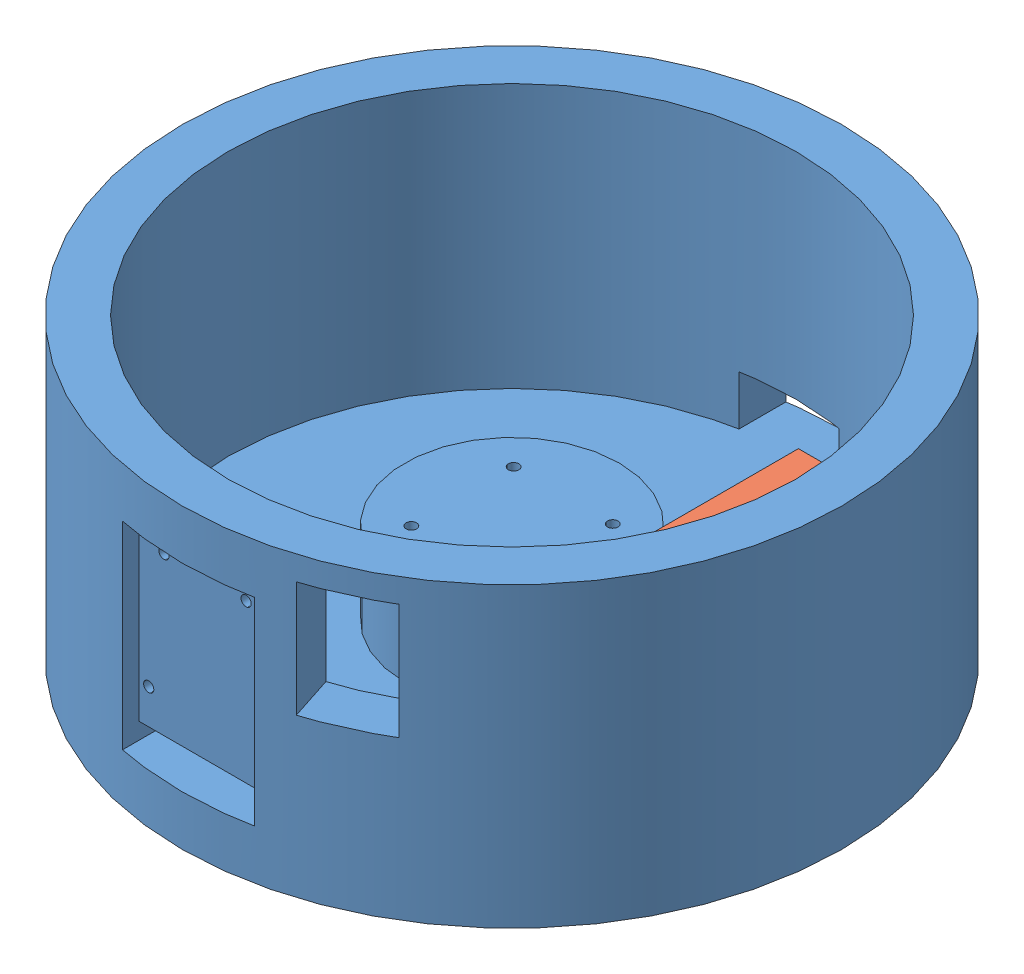
SolidWorks assembly Assem3, configuration Default. Lengths in mm.
Overall size (200 90.1 200).
2 component instances, 2 part files, 2 mates.
Components (placement in the parent):
- pilldispenserbase-1: pilldispenserbase [Default] at (89.2074 78.3474 163.5179) size (200 90.1 200)
- motor_driver-1: motor_driver [Default] at (162.5728 110.8474 162.627) x (0 1 0) z (0 0 1) size (45 30 85)
Mates (geometry in assembly coordinates):
- Parallel1: parallel anti-aligned: plane of motor_driver-1 through (132.5728 110.8474 162.627) normal (-1 0 0)
- Coincident2: coincident anti-aligned: plane of pilldispenserbase-1 through (89.2074 88.3474 163.5179) normal (0 1 0); plane of motor_driver-1 through (132.5728 88.3474 205.127) normal (0 -1 0)
